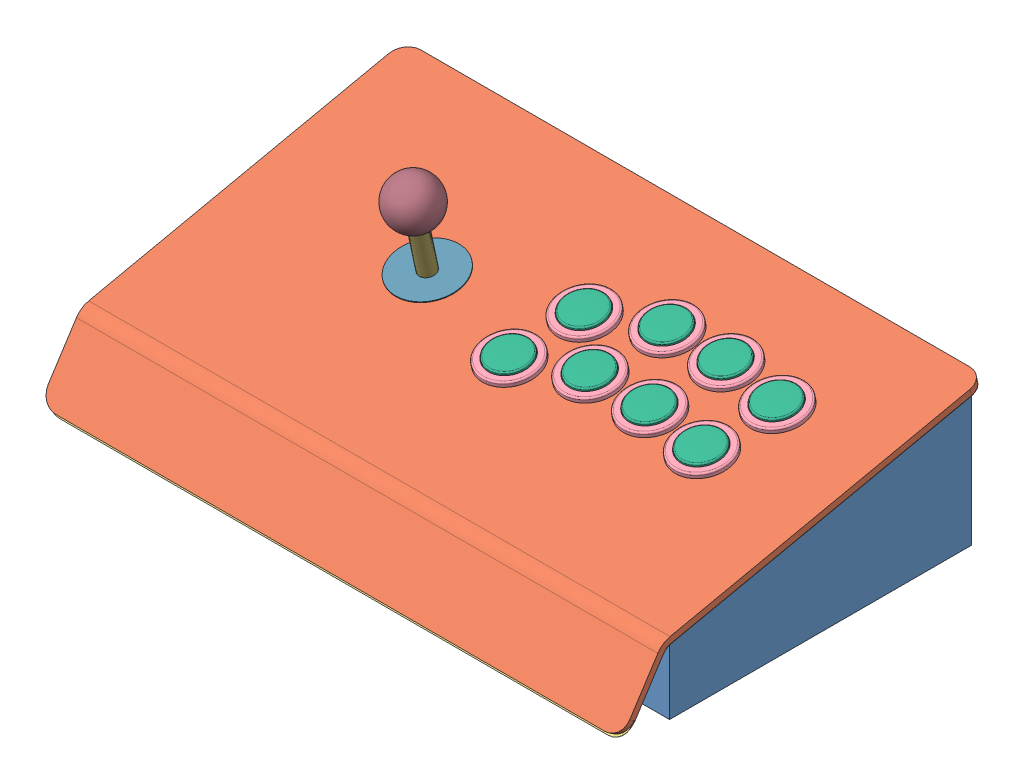
SolidWorks assembly Ensamblaje1, configuration Predeterminado. Lengths in mm.
Overall size (360 132.15 240.73).
45 component instances, 15 part files, 24 mates.
Components (placement in the parent):
- Arcadia v1 - BOX 1-1: Arcadia v1 - BOX 1 [Predeterminado] at (-40.764 -21.9254 360) size (360 80 187)
- Arcadia v1 - TOP 1-2: Arcadia v1 - TOP 1 [Predeterminado] at (-40.764 62.3177 257.1814) x (1 0 0) z (0 0.977879 0.209172) size (360 238.29 36.14)
- Arcadia v1 - TOP_tex-1: Arcadia v1 - TOP_tex [Predeterminado] at (-40.764 60.2641 256.7421) x (1 0 0) z (0 0.977879 0.209172) size (360 236.94 32.9)
- sanwa_button_00_asm_6-1: sanwa_button_00_asm_6 [Predeterminado] at (-41.264 25.1321 368.874) x (1 0 0) z (0 -0.209172 0.977879) size (34 37.41 37.09)
  - sanwa_button_00_11-1: sanwa_button_00_11 [Predeterminado] at origin size (34 22.2 37.09)
  - black_00_3-1: black_00_3 [Predeterminado] at (0 5 0) x (-1 0 0) z (0 0 1) size (14 26.9 14)
  - sanwa_button_02_8-1: sanwa_button_02_8 [Predeterminado] at (0 17 0) x (0 0 -1) z (1 0 0) size (25 13.51 28.68)
- sanwa_button_00_asm_6-2: sanwa_button_00_asm_6 [Predeterminado] at (39.736 36.532 315.5796) x (0.999777 -0.004416 0.020646) z (-0.021113 -0.209125 0.977661) size (34 37.41 37.09)
  - sanwa_button_00_11-1: sanwa_button_00_11 [Predeterminado] at origin size (34 22.2 37.09)
  - black_00_3-1: black_00_3 [Predeterminado] at (0 5 0) x (-1 0 0) z (0 0 1) size (14 26.9 14)
  - sanwa_button_02_8-1: sanwa_button_02_8 [Predeterminado] at (0 17 0) x (0 0 -1) z (1 0 0) size (25 13.51 28.68)
- sanwa_button_00_asm_6-3: sanwa_button_00_asm_6 [Predeterminado] at (76.736 35.3815 320.9579) x (0.999777 -0.004416 0.020646) z (-0.021113 -0.209125 0.977661) size (34 37.41 37.09)
  - sanwa_button_00_11-1: sanwa_button_00_11 [Predeterminado] at origin size (34 22.2 37.09)
  - black_00_3-1: black_00_3 [Predeterminado] at (0 5 0) x (-1 0 0) z (0 0 1) size (14 26.9 14)
  - sanwa_button_02_8-1: sanwa_button_02_8 [Predeterminado] at (0 17 0) x (0 0 -1) z (1 0 0) size (25 13.51 28.68)
- sanwa_button_00_asm_6-4: sanwa_button_00_asm_6 [Predeterminado] at (3.236 36.532 315.5796) x (0.999777 -0.004416 0.020646) z (-0.021113 -0.209125 0.977661) size (34 37.41 37.09)
  - sanwa_button_00_11-1: sanwa_button_00_11 [Predeterminado] at origin size (34 22.2 37.09)
  - black_00_3-1: black_00_3 [Predeterminado] at (0 5 0) x (-1 0 0) z (0 0 1) size (14 26.9 14)
  - sanwa_button_02_8-1: sanwa_button_02_8 [Predeterminado] at (0 17 0) x (0 0 -1) z (1 0 0) size (25 13.51 28.68)
- sanwa_button_00_asm_6-5: sanwa_button_00_asm_6 [Predeterminado] at (32.236 28.0605 355.1837) x (0.999777 -0.004416 0.020646) z (-0.021113 -0.209125 0.977661) size (34 37.41 37.09)
  - sanwa_button_00_11-1: sanwa_button_00_11 [Predeterminado] at origin size (34 22.2 37.09)
  - black_00_3-1: black_00_3 [Predeterminado] at (0 5 0) x (-1 0 0) z (0 0 1) size (14 26.9 14)
  - sanwa_button_02_8-1: sanwa_button_02_8 [Predeterminado] at (0 17 0) x (0 0 -1) z (1 0 0) size (25 13.51 28.68)
- sanwa_button_00_asm_6-6: sanwa_button_00_asm_6 [Predeterminado] at (-4.764 28.0605 355.1837) x (0.999777 -0.004416 0.020646) z (-0.021113 -0.209125 0.977661) size (34 37.41 37.09)
  - sanwa_button_00_11-1: sanwa_button_00_11 [Predeterminado] at origin size (34 22.2 37.09)
  - black_00_3-1: black_00_3 [Predeterminado] at (0 5 0) x (-1 0 0) z (0 0 1) size (14 26.9 14)
  - sanwa_button_02_8-1: sanwa_button_02_8 [Predeterminado] at (0 17 0) x (0 0 -1) z (1 0 0) size (25 13.51 28.68)
- sanwa_button_00_asm_6-7: sanwa_button_00_asm_6 [Predeterminado] at (69.236 27.0147 360.0731) x (0.999777 -0.004416 0.020646) z (-0.021113 -0.209125 0.977661) size (34 37.41 37.09)
  - sanwa_button_00_11-1: sanwa_button_00_11 [Predeterminado] at origin size (34 22.2 37.09)
  - black_00_3-1: black_00_3 [Predeterminado] at (0 5 0) x (-1 0 0) z (0 0 1) size (14 26.9 14)
  - sanwa_button_02_8-1: sanwa_button_02_8 [Predeterminado] at (0 17 0) x (0 0 -1) z (1 0 0) size (25 13.51 28.68)
- sanwa_button_00_asm_6-8: sanwa_button_00_asm_6 [Predeterminado] at (-33.764 33.499 329.7588) x (0.999777 -0.004416 0.020646) z (-0.021113 -0.209125 0.977661) size (34 37.41 37.09)
  - sanwa_button_00_11-1: sanwa_button_00_11 [Predeterminado] at origin size (34 22.2 37.09)
  - black_00_3-1: black_00_3 [Predeterminado] at (0 5 0) x (-1 0 0) z (0 0 1) size (14 26.9 14)
  - sanwa_button_02_8-1: sanwa_button_02_8 [Predeterminado] at (0 17 0) x (0 0 -1) z (1 0 0) size (25 13.51 28.68)
- Joystick Sanwa -Mod JLF-TP-8YT-W 1-1: Joystick Sanwa -Mod JLF-TP-8YT-W 1 [Predeterminado] at (-110.764 38.2006 352.2396) x (0 0.209172 -0.977879) z (0 -0.977879 -0.209172) size (100 66.68 104.46)
  - SANWA_JOYSTICK_3-1: SANWA_JOYSTICK_3 [Predeterminado] at origin size (100 60 1.5)
  - SSANWA_JOYSTICK_6-1: SSANWA_JOYSTICK_6 [Predeterminado] at origin size (66 60 30)
  - SANWA_JOYSTICK_2-1: SANWA_JOYSTICK_2 [Predeterminado] x (1 0 0) z (0 1 0) size (39.99 20.68 39.98)
  - SANWA_JOYSTICK_5-1: SANWA_JOYSTICK_5 [Predeterminado] at (0 0 12.592) x (1 0 0) z (0 0 -1) size (66.1 66.68 17.11)
  - GT-Y-1: GT-Y [Predeterminado] at (0 0 27.552) size (60 60 10)
  - SANWA_JOYSTICK_0-1: SANWA_JOYSTICK_0 [Predeterminado] at (0 0 7.5029) x (0.996812 -0.079782 0) z (0.079782 0.996812 0) size (10 85 10)
  - BALL-1: BALL [Predeterminado] at (0 0 -47.9539) x (0.999996 -0.002826 0) z (0.002826 0.999996 0) size (30 30 30)
  - DUSTER-1: DUSTER [Predeterminado] at (0 0 -6.2) x (-1 0 0) z (0 0 1) size (40 40 0.5)
  - E-1: E [Predeterminado] at (0 0 39.0029) x (0.999996 -0.002826 0) z (0.002826 0.999996 0) size (5.88 1.1 10)
Mates (geometry in assembly coordinates):
- Coincidente6: coincident anti-aligned: plane of Arcadia v1 - TOP 1-2 through (139.236 64.2734 257.5997) normal (0 0.977879 0.209172); circle of sanwa_button_00_asm_6-1/sanwa_button_00_11-1
- Coincidente7: coincident anti-aligned: plane of Arcadia v1 - TOP 1-2 through (139.236 60.3619 256.763) normal (0 -0.977879 -0.209172); plane of Arcadia v1 - TOP_tex-1 through (139.236 60.3619 256.763) normal (0 0.977879 0.209172)
- Coincidente8: coincident aligned: plane of Arcadia v1 - TOP 1-2 through (-220.764 10.7045 450.6654) normal (-1 0 0); plane of Arcadia v1 - TOP_tex-1 through (-220.764 8.6509 450.2262) normal (-1 0 0)
- Coincidente10: coincident aligned: plane of Arcadia v1 - TOP 1-2 through (139.236 64.2734 257.5997) normal (0 0.209172 -0.977879); plane of Arcadia v1 - TOP_tex-1 through (139.236 60.3619 256.763) normal (0 0.209172 -0.977879)
- Coincidente12: coincident anti-aligned: plane of Arcadia v1 - TOP 1-2 through (139.236 64.2734 257.5997) normal (0 0.977879 0.209172); plane of sanwa_button_00_asm_6-3/sanwa_button_00_11-1 through (76.736 50.0497 324.0955) normal (0 -0.977879 -0.209172)
- Coincidente13: coincident anti-aligned: plane of Arcadia v1 - TOP 1-2 through (139.236 64.2734 257.5997) normal (0 0.977879 0.209172); plane of sanwa_button_00_asm_6-2/sanwa_button_00_11-1 through (39.736 51.2002 318.7172) normal (0 -0.977879 -0.209172)
- Coincidente14: coincident anti-aligned: plane of Arcadia v1 - TOP 1-2 through (139.236 64.2734 257.5997) normal (0 0.977879 0.209172); plane of sanwa_button_00_asm_6-4/sanwa_button_00_11-1 through (3.236 51.2002 318.7172) normal (0 -0.977879 -0.209172)
- Coincidente15: coincident anti-aligned: plane of Arcadia v1 - TOP 1-2 through (139.236 64.2734 257.5997) normal (0 0.977879 0.209172); plane of sanwa_button_00_asm_6-8/sanwa_button_00_11-1 through (-33.764 48.1672 332.8964) normal (0 -0.977879 -0.209172)
- Coincidente16: coincident anti-aligned: plane of Arcadia v1 - TOP 1-2 through (139.236 64.2734 257.5997) normal (0 0.977879 0.209172); plane of sanwa_button_00_asm_6-6/sanwa_button_00_11-1 through (-4.764 42.7287 358.3213) normal (0 -0.977879 -0.209172)
- Coincidente17: coincident anti-aligned: plane of Arcadia v1 - TOP 1-2 through (139.236 64.2734 257.5997) normal (0 0.977879 0.209172); plane of sanwa_button_00_asm_6-5/sanwa_button_00_11-1 through (32.236 42.7287 358.3213) normal (0 -0.977879 -0.209172)
- Coincidente18: coincident anti-aligned: plane of Arcadia v1 - TOP 1-2 through (139.236 64.2734 257.5997) normal (0 0.977879 0.209172); plane of sanwa_button_00_asm_6-7/sanwa_button_00_11-1 through (69.236 41.6828 363.2107) normal (0 -0.977879 -0.209172)
- Coincidente19: coincident anti-aligned: line of Arcadia v1 - BOX 1-1 through (139.236 58.0746 266.5) axis (0 -0.209172 0.977879); line of Arcadia v1 - TOP_tex-1 through (139.236 18.3319 452.297) axis (0 0.209172 -0.977879)
- Coincidente20: coincident anti-aligned: line of Arcadia v1 - BOX 1-1 through (-220.764 58.0746 266.5) axis (0 -0.209172 0.977879); line of Arcadia v1 - TOP_tex-1 through (-220.764 18.3319 452.297) axis (0 0.209172 -0.977879)
- Distancia4: distance = 10 mm: line of Arcadia v1 - TOP_tex-1 through (129.236 60.1663 256.7212) axis (-1 0 0); line of Arcadia v1 - BOX 1-1 through (139.236 58.0746 266.5) axis (-1 0 0)
- Concéntrica1: concentric anti-aligned: circle of Arcadia v1 - TOP 1-2; cylinder of sanwa_button_00_asm_6-1/sanwa_button_00_11-1 through (-41.264 43.614 372.8273) axis (0 -0.977879 -0.209172) radius 15
- Concéntrica2: concentric anti-aligned: cylinder of Arcadia v1 - TOP 1-2 through (-33.764 12.8219 325.3359) axis (0 0.977879 0.209172) radius 15.7; cylinder of sanwa_button_00_asm_6-8/sanwa_button_00_11-1 through (-33.764 51.9809 333.7122) axis (0 -0.977879 -0.209172) radius 17
- Concéntrica3: concentric anti-aligned: cylinder of Arcadia v1 - TOP 1-2 through (3.236 15.8549 311.1567) axis (0 0.977879 0.209172) radius 15.7; cylinder of sanwa_button_00_asm_6-4/sanwa_button_00_11-1 through (3.236 55.0139 319.5329) axis (0 -0.977879 -0.209172) radius 17
- Concéntrica4: concentric anti-aligned: cylinder of Arcadia v1 - TOP 1-2 through (39.736 15.8549 311.1567) axis (0 0.977879 0.209172) radius 15.7; cylinder of sanwa_button_00_asm_6-2/sanwa_button_00_11-1 through (39.736 55.0139 319.5329) axis (0 -0.977879 -0.209172) radius 17
- Concéntrica5: concentric anti-aligned: cylinder of Arcadia v1 - TOP 1-2 through (76.736 14.7044 316.535) axis (0 0.977879 0.209172) radius 15.7; cylinder of sanwa_button_00_asm_6-3/sanwa_button_00_11-1 through (76.736 53.8634 324.9113) axis (0 -0.977879 -0.209172) radius 17
- Concéntrica6: concentric anti-aligned: cylinder of Arcadia v1 - TOP 1-2 through (-4.764 7.3834 350.7608) axis (0 0.977879 0.209172) radius 15.7; cylinder of sanwa_button_00_asm_6-6/sanwa_button_00_11-1 through (-4.764 46.5424 359.137) axis (0 -0.977879 -0.209172) radius 17
- Concéntrica7: concentric anti-aligned: cylinder of Arcadia v1 - TOP 1-2 through (32.236 7.3834 350.7608) axis (0 0.977879 0.209172) radius 15.7; cylinder of sanwa_button_00_asm_6-5/sanwa_button_00_11-1 through (32.236 46.5424 359.137) axis (0 -0.977879 -0.209172) radius 17
- Concéntrica8: concentric anti-aligned: cylinder of Arcadia v1 - TOP 1-2 through (69.236 6.3375 355.6502) axis (0 0.977879 0.209172) radius 15.7; cylinder of sanwa_button_00_asm_6-7/sanwa_button_00_11-1 through (69.236 45.4966 364.0264) axis (0 -0.977879 -0.209172) radius 17
- Coincidente25: coincident anti-aligned: plane of Arcadia v1 - TOP 1-2 through (139.236 64.2734 257.5997) normal (0 0.977879 0.209172); plane of Joystick Sanwa -Mod JLF-TP-8YT-W 1-1/DUSTER-1 through (-110.764 43.7746 353.4319) normal (0 -0.977879 -0.209172)
- Concéntrica9: concentric anti-aligned: cylinder of Arcadia v1 - TOP 1-2 through (-110.764 8.4293 345.8714) axis (0 0.977879 0.209172) radius 12.4506; cylinder of Joystick Sanwa -Mod JLF-TP-8YT-W 1-1/SANWA_JOYSTICK_0-1 through (-110.764 30.8637 350.6702) axis (0 -0.977879 -0.209172) radius 5
